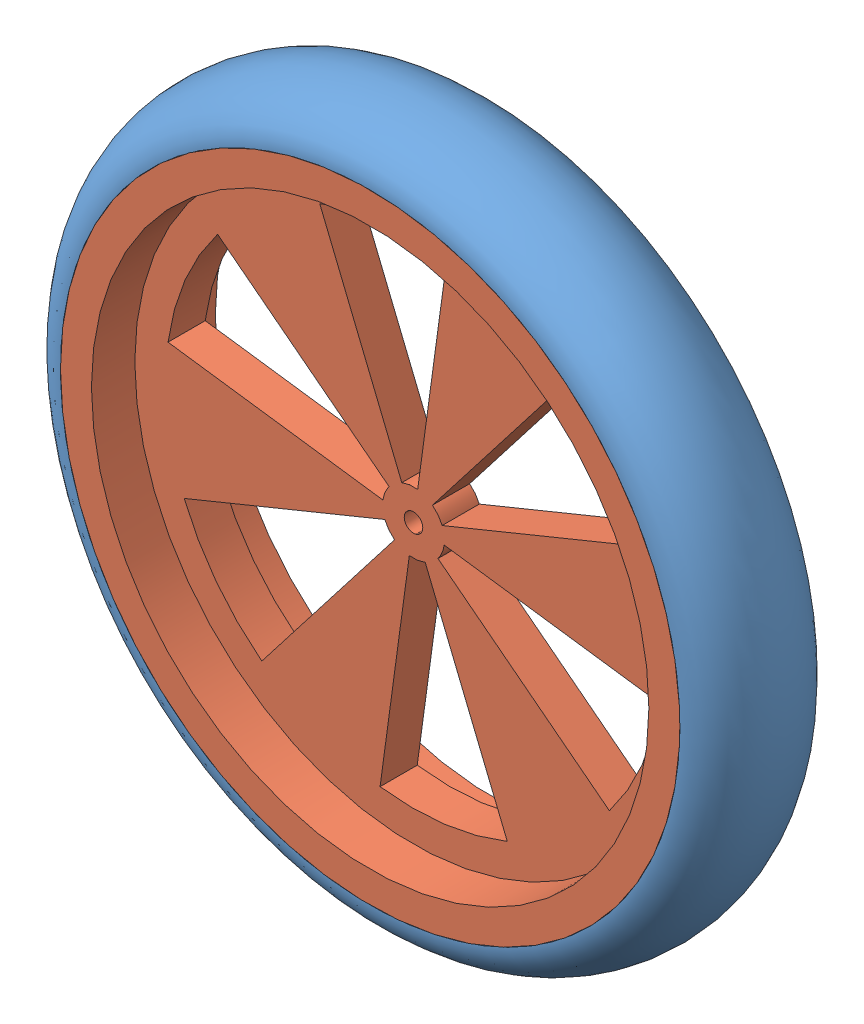
SolidWorks assembly roue200-2, configuration Défaut. Lengths in mm.
Overall size (114 114 20).
2 component instances, 2 part files, 1 mates.
Components (placement in the parent):
- pneu-200-2-1: pneu-200-2 [Défaut] at (1.9727 4.6283 114) size (114 114 20)
- jante10-2-1: jante10-2 [Défaut] at (1.9727 4.6283 104) size (100 100 20)
Mates (geometry in assembly coordinates):
- Coïncidente1: coincident aligned: circle of pneu-200-2-1; circle of jante10-2-1
